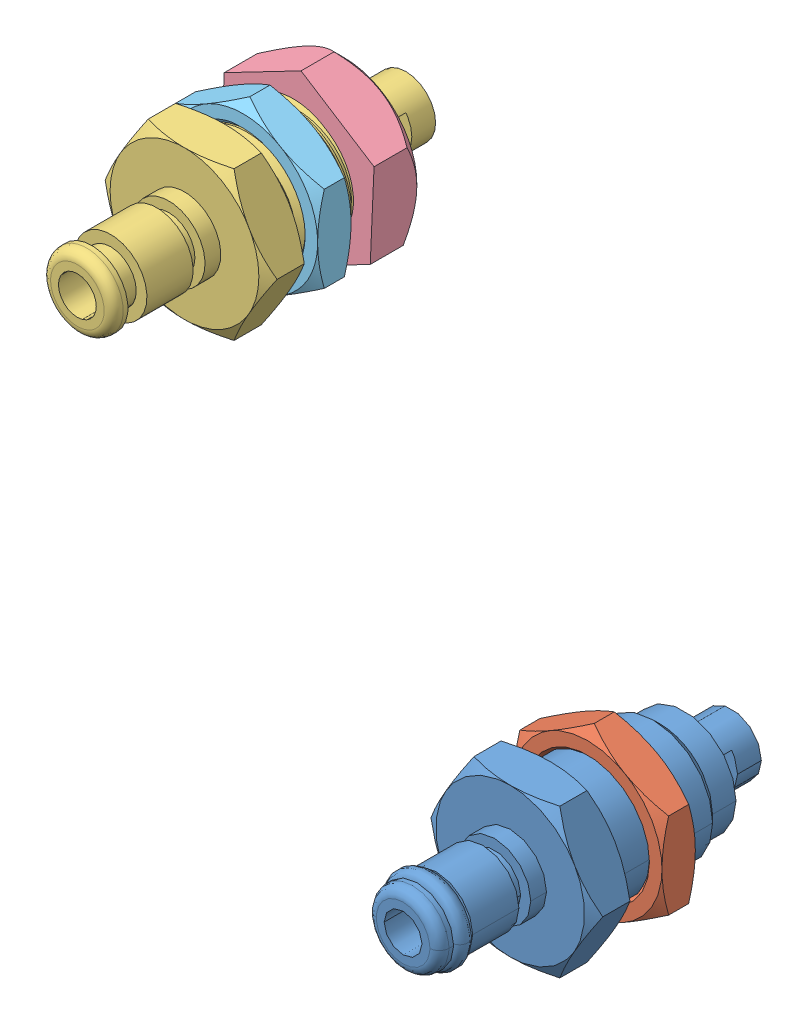
SolidWorks assembly PMC4201, configuration Default. Lengths in mm.
Overall size (60.47 56.74 40.31).
5 component instances, 5 part files, 2 mates.
Components (placement in the parent):
- _PMC4201_BODY_2-1: _PMC4201_BODY_2 [Default] at origin size (18.33 20.47 35.05)
- _100901_4-1: _100901_4 [Default] at (0 0 -19.685) size (20.47 18.33 3.57)
- Part12-1: Part12 [Default] at (-40.0067 36.2729 -5.2537) size (18.33 20.47 35.05)
- Nut-1: Nut [Default] at (-40.0067 36.2729 -33.7135) x (1 0 0) z (0 -1 0) size (18.23 6 20.3)
- Nut2-1: Nut2 [Default] at (-40.0067 36.2729 -22.9558) size (20.47 18.33 4.42)
Mates (geometry in assembly coordinates):
- Concentric1: concentric aligned: circle of Part12-1; circle of Nut2-1
- Concentric2: concentric anti-aligned: circle of Part12-1; circle of Nut-1
